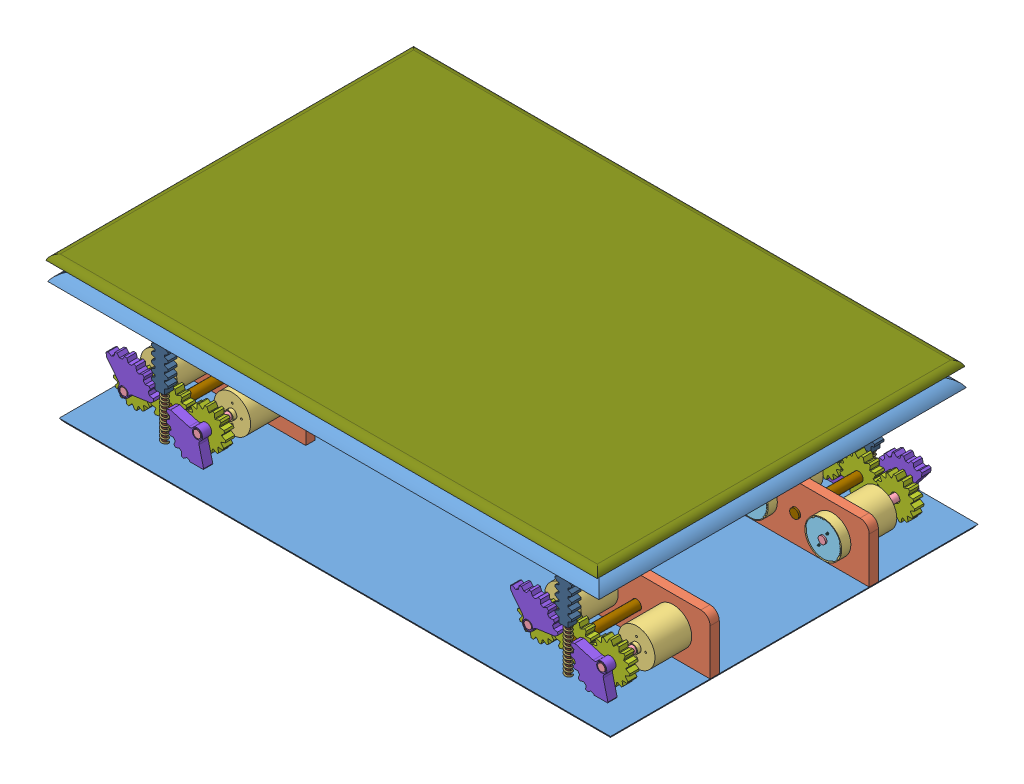
SolidWorks assembly Final Assembly, configuration Default. Lengths in mm.
Overall size (303.51 82.44 203.65).
112 component instances, 16 part files, 27 mates.
Components (placement in the parent):
- Assem6^Final Assembly-1: Assem6^Final Assembly [Default] at (14.902 -247.6382 47.2296) size (300 5 200) (virtual)
  - Floor-1: Floor [Default] at (40.4183 145.2122 322.6651) x (1 0 0) z (0 -1 0) size (300 200 5)
- Main assembly-1: Main assembly [Default] at (183.7252 -136.3252 264.8506) size (80 37.19 50)
  - motor holder-1: motor holder [Default] at (33.3269 70.8172 72.9987) size (80 30 5)
  - Motor-1: Motor [Default] at (25.9091 64.8426 109.725) x (0.51883 -0.854877 0) z (0 0 -1) size (20 20 50)
    - motorcover-1: motorcover [Default] at (7.4227 18.4991 11.7262) size (20 20 32)
    - dynamo-1: dynamo [Default] at (7.4227 18.4991 32.5262) x (0.962292 0.27202 0) z (0 0 -1) size (15 15 50)
    - Backcover-1: Backcover [Default] at (7.4227 18.4991 40.9262) size (19.2 19.2 0.8)
    - pin-1: pin [Default] at (28.5286 14.4912 41.7262) x (1 0 0) z (0 0 -1) size (1.25 1 1.6)
    - pin-2: pin [Default] at (37.5286 14.4917 41.7262) x (1 0 0) z (0 0 -1) size (1.25 1 1.6)
  - Motor-2: Motor [Default] at (46.523 67.3984 109.725) x (1 0 0) z (0 0 -1) size (20 20 50)
    - motorcover-1: motorcover [Default] at (7.4227 18.4991 11.7262) size (20 20 32)
    - dynamo-1: dynamo [Default] at (7.4227 18.4991 32.5262) x (0.962292 0.27202 0) z (0 0 -1) size (15 15 50)
    - Backcover-1: Backcover [Default] at (7.4227 18.4991 40.9262) size (19.2 19.2 0.8)
    - pin-1: pin [Default] at (28.5286 14.4912 41.7262) x (1 0 0) z (0 0 -1) size (1.25 1 1.6)
    - pin-2: pin [Default] at (37.5286 14.4917 41.7262) x (1 0 0) z (0 0 -1) size (1.25 1 1.6)
  - Spur gear-1: Spur gear [Default] at (13.9457 48.8992 107.1987) x (-0.96785 0.251527 0) z (0 0 1) size (21.02 20.91 5)
  - Spur gear-2: Spur gear [Default] at (53.9457 48.8992 107.1987) x (-0.973351 -0.229319 0) z (0 0 1) size (21.02 20.91 5)
  - Rack gear-1: Rack gear [Default] at (13.9457 48.8992 112.1987) x (0.990037 0.14081 0) z (0 0 1) size (24.29 19.79 5)
  - Rack gear-2: Rack gear [Default] at (53.9457 48.8992 112.1987) x (-0.960989 0.276587 0) z (0 0 1) size (24.29 19.79 5)
  - Spur gear-3: Spur gear [Default] at (33.9457 48.8992 107.1987) x (-0.999731 0.023183 0) z (0 0 1) size (21.02 20.91 5)
  - Rod1-2: Rod1 [Default] at (33.9457 48.8992 72.1987) size (5 5 40)
- Main assembly-2: Main assembly [Default] at (-36.2748 -136.3252 264.8506) size (80 37.19 50)
  - motor holder-1: motor holder [Default] at (33.3269 70.8172 72.9987) size (80 30 5)
  - Motor-1: Motor [Default] at (25.9091 64.8426 109.725) x (0.51883 -0.854877 0) z (0 0 -1) size (20 20 50)
    - motorcover-1: motorcover [Default] at (7.4227 18.4991 11.7262) size (20 20 32)
    - dynamo-1: dynamo [Default] at (7.4227 18.4991 32.5262) x (0.962292 0.27202 0) z (0 0 -1) size (15 15 50)
    - Backcover-1: Backcover [Default] at (7.4227 18.4991 40.9262) size (19.2 19.2 0.8)
    - pin-1: pin [Default] at (28.5286 14.4912 41.7262) x (1 0 0) z (0 0 -1) size (1.25 1 1.6)
    - pin-2: pin [Default] at (37.5286 14.4917 41.7262) x (1 0 0) z (0 0 -1) size (1.25 1 1.6)
  - Motor-2: Motor [Default] at (46.523 67.3984 109.725) x (1 0 0) z (0 0 -1) size (20 20 50)
    - motorcover-1: motorcover [Default] at (7.4227 18.4991 11.7262) size (20 20 32)
    - dynamo-1: dynamo [Default] at (7.4227 18.4991 32.5262) x (0.962292 0.27202 0) z (0 0 -1) size (15 15 50)
    - Backcover-1: Backcover [Default] at (7.4227 18.4991 40.9262) size (19.2 19.2 0.8)
    - pin-1: pin [Default] at (28.5286 14.4912 41.7262) x (1 0 0) z (0 0 -1) size (1.25 1 1.6)
    - pin-2: pin [Default] at (37.5286 14.4917 41.7262) x (1 0 0) z (0 0 -1) size (1.25 1 1.6)
  - Spur gear-1: Spur gear [Default] at (13.9457 48.8992 107.1987) x (-0.96785 0.251527 0) z (0 0 1) size (21.02 20.91 5)
  - Spur gear-2: Spur gear [Default] at (53.9457 48.8992 107.1987) x (-0.973351 -0.229319 0) z (0 0 1) size (21.02 20.91 5)
  - Rack gear-1: Rack gear [Default] at (13.9457 48.8992 112.1987) x (0.990037 0.14081 0) z (0 0 1) size (24.29 19.79 5)
  - Rack gear-2: Rack gear [Default] at (53.9457 48.8992 112.1987) x (-0.960989 0.276587 0) z (0 0 1) size (24.29 19.79 5)
  - Spur gear-3: Spur gear [Default] at (33.9457 48.8992 107.1987) x (-0.999731 0.023183 0) z (0 0 1) size (21.02 20.91 5)
  - Rod1-2: Rod1 [Default] at (33.9457 48.8992 72.1987) size (5 5 40)
- Pinion assembly with spring-1: Pinion assembly with spring [Default] at (-23.5736 0.0132 350.0039) x (1 0 0) z (0 -1 0) size (9 6.09 65.24)
  - pinion gear-1: pinion gear [Default] at (18.4826 32.0454 18.0009) x (0 0 1) z (0 -1 0) size (40 9 5)
  - Rod-1: Rod [Default] at (20.9826 29.4437 42.4391) x (-0.885268 -0.465081 0) z (0 0 1) size (2 2 60)
  - spring-1: spring [Default] at (20.9826 29.4437 61.9854) x (-0.695169 0.718847 0) z (0.718847 0.695169 0) size (4 30.64 4.62)
  - base-1: base [Default] at (20.9826 29.4437 102.4391) x (-0.953699 0.300764 0) z (0 0 1) size (4 4 0.4)
- Pinion assembly with spring-2: Pinion assembly with spring [Default] at (196.0946 0.0132 350.0039) x (1 0 0) z (0 -1 0) size (9 6.09 65.24)
  - pinion gear-1: pinion gear [Default] at (18.4826 32.0454 18.0009) x (0 0 1) z (0 -1 0) size (40 9 5)
  - Rod-1: Rod [Default] at (20.9826 29.4437 42.4391) x (-0.885268 -0.465081 0) z (0 0 1) size (2 2 60)
  - spring-1: spring [Default] at (20.9826 29.4437 61.9854) x (-0.695169 0.718847 0) z (0.718847 0.695169 0) size (4 30.64 4.62)
  - base-1: base [Default] at (20.9826 29.4437 102.4391) x (-0.953699 0.300764 0) z (0 0 1) size (4 4 0.4)
- Pinion assembly with spring-3: Pinion assembly with spring [Default] at (-24.0061 0.0132 185.0039) x (1 0 0) z (0 -1 0) size (9 6.09 65.24)
  - pinion gear-1: pinion gear [Default] at (18.4826 32.0454 18.0009) x (0 0 1) z (0 -1 0) size (40 9 5)
  - Rod-1: Rod [Default] at (20.9826 29.4437 42.4391) x (-0.885268 -0.465081 0) z (0 0 1) size (2 2 60)
  - spring-1: spring [Default] at (20.9826 29.4437 61.9854) x (-0.695169 0.718847 0) z (0.718847 0.695169 0) size (4 30.64 4.62)
  - base-1: base [Default] at (20.9826 29.4437 102.4391) x (-0.953699 0.300764 0) z (0 0 1) size (4 4 0.4)
- Pinion assembly with spring-4: Pinion assembly with spring [Default] at (195.948 0.0132 185.0039) x (1 0 0) z (0 -1 0) size (9 6.09 65.24)
  - pinion gear-1: pinion gear [Default] at (18.4826 32.0454 18.0009) x (0 0 1) z (0 -1 0) size (40 9 5)
  - Rod-1: Rod [Default] at (20.9826 29.4437 42.4391) x (-0.885268 -0.465081 0) z (0 0 1) size (2 2 60)
  - spring-1: spring [Default] at (20.9826 29.4437 61.9854) x (-0.695169 0.718847 0) z (0.718847 0.695169 0) size (4 30.64 4.62)
  - base-1: base [Default] at (20.9826 29.4437 102.4391) x (-0.953699 0.300764 0) z (0 0 1) size (4 4 0.4)
- Floor-2: Floor [Default] at (52.166 -37.9877 227.3464) x (1 0 0) z (0 1 0) size (300 200 5)
- piezo-holder-1: piezo-holder [Default] at (-34.8513 -27.9877 210.389) x (1 0 0) z (0 -1 0) size (5 5 5)
- piezo-holder-2: piezo-holder [Default] at (244.0539 -27.9877 207.1198) x (1 0 0) z (0 -1 0) size (5 5 5)
- piezo-holder-3: piezo-holder [Default] at (-35.2045 -27.9877 389.6264) x (1 0 0) z (0 -1 0) size (5 5 5)
- piezo-holder-4: piezo-holder [Default] at (243.3873 -27.9877 391.1396) x (1 0 0) z (0 -1 0) size (5 5 5)
- Spring2-2: Spring2 [Default] at (244.0033 -32.8878 207.2172) x (1 0 0) z (0 -0.048057 0.998845) size (6.2 5.2 7.16)
- Spring2-3: Spring2 [Default] at (243.1158 -33.0876 391.053) x (1 0 0) z (0 -0.048057 0.998845) size (6.2 5.2 7.16)
- Spring2-5: Spring2 [Default] at (-35.5943 -32.8878 389.5788) x (1 0 0) z (0 -0.048057 0.998845) size (6.2 5.2 7.16)
- Spring2-6: Spring2 [Default] at (-34.8112 -32.8878 210.5266) x (1 0 0) z (0 -0.048057 0.998845) size (6.2 5.2 7.16)
- footbase-2: footbase [Default] at (2.9353 -27.9877 217.7245) x (1 0 0) z (0 1 0) size (300 200 10)
- Main assembly-5: Main assembly [Default] at (31.6166 -136.3252 329.248) x (-1 0 0) z (0 0 -1) size (80 37.19 50)
  - motor holder-1: motor holder [Default] at (33.3269 70.8172 72.9987) size (80 30 5)
  - Motor-1: Motor [Default] at (25.9091 64.8426 109.725) x (0.51883 -0.854877 0) z (0 0 -1) size (20 20 50)
    - motorcover-1: motorcover [Default] at (7.4227 18.4991 11.7262) size (20 20 32)
    - dynamo-1: dynamo [Default] at (7.4227 18.4991 32.5262) x (0.962292 0.27202 0) z (0 0 -1) size (15 15 50)
    - Backcover-1: Backcover [Default] at (7.4227 18.4991 40.9262) size (19.2 19.2 0.8)
    - pin-1: pin [Default] at (28.5286 14.4912 41.7262) x (1 0 0) z (0 0 -1) size (1.25 1 1.6)
    - pin-2: pin [Default] at (37.5286 14.4917 41.7262) x (1 0 0) z (0 0 -1) size (1.25 1 1.6)
  - Motor-2: Motor [Default] at (46.523 67.3984 109.725) x (1 0 0) z (0 0 -1) size (20 20 50)
    - motorcover-1: motorcover [Default] at (7.4227 18.4991 11.7262) size (20 20 32)
    - dynamo-1: dynamo [Default] at (7.4227 18.4991 32.5262) x (0.962292 0.27202 0) z (0 0 -1) size (15 15 50)
    - Backcover-1: Backcover [Default] at (7.4227 18.4991 40.9262) size (19.2 19.2 0.8)
    - pin-1: pin [Default] at (28.5286 14.4912 41.7262) x (1 0 0) z (0 0 -1) size (1.25 1 1.6)
    - pin-2: pin [Default] at (37.5286 14.4917 41.7262) x (1 0 0) z (0 0 -1) size (1.25 1 1.6)
  - Spur gear-1: Spur gear [Default] at (13.9457 48.8992 107.1987) x (-0.96785 0.251527 0) z (0 0 1) size (21.02 20.91 5)
  - Spur gear-2: Spur gear [Default] at (53.9457 48.8992 107.1987) x (-0.973351 -0.229319 0) z (0 0 1) size (21.02 20.91 5)
  - Rack gear-1: Rack gear [Default] at (13.9457 48.8992 112.1987) x (0.990037 0.14081 0) z (0 0 1) size (24.29 19.79 5)
  - Rack gear-2: Rack gear [Default] at (53.9457 48.8992 112.1987) x (-0.960989 0.276587 0) z (0 0 1) size (24.29 19.79 5)
  - Spur gear-3: Spur gear [Default] at (33.9457 48.8992 107.1987) x (-0.999731 0.023183 0) z (0 0 1) size (21.02 20.91 5)
  - Rod1-2: Rod1 [Default] at (33.9457 48.8992 72.1987) size (5 5 40)
- Main assembly-6: Main assembly [Default] at (251.6166 -136.3252 329.248) x (-1 0 0) z (0 0 -1) size (80 37.19 50)
  - motor holder-1: motor holder [Default] at (33.3269 70.8172 72.9987) size (80 30 5)
  - Motor-1: Motor [Default] at (25.9091 64.8426 109.725) x (0.51883 -0.854877 0) z (0 0 -1) size (20 20 50)
    - motorcover-1: motorcover [Default] at (7.4227 18.4991 11.7262) size (20 20 32)
    - dynamo-1: dynamo [Default] at (7.4227 18.4991 32.5262) x (0.962292 0.27202 0) z (0 0 -1) size (15 15 50)
    - Backcover-1: Backcover [Default] at (7.4227 18.4991 40.9262) size (19.2 19.2 0.8)
    - pin-1: pin [Default] at (28.5286 14.4912 41.7262) x (1 0 0) z (0 0 -1) size (1.25 1 1.6)
    - pin-2: pin [Default] at (37.5286 14.4917 41.7262) x (1 0 0) z (0 0 -1) size (1.25 1 1.6)
  - Motor-2: Motor [Default] at (46.523 67.3984 109.725) x (1 0 0) z (0 0 -1) size (20 20 50)
    - motorcover-1: motorcover [Default] at (7.4227 18.4991 11.7262) size (20 20 32)
    - dynamo-1: dynamo [Default] at (7.4227 18.4991 32.5262) x (0.962292 0.27202 0) z (0 0 -1) size (15 15 50)
    - Backcover-1: Backcover [Default] at (7.4227 18.4991 40.9262) size (19.2 19.2 0.8)
    - pin-1: pin [Default] at (28.5286 14.4912 41.7262) x (1 0 0) z (0 0 -1) size (1.25 1 1.6)
    - pin-2: pin [Default] at (37.5286 14.4917 41.7262) x (1 0 0) z (0 0 -1) size (1.25 1 1.6)
  - Spur gear-1: Spur gear [Default] at (13.9457 48.8992 107.1987) x (-0.96785 0.251527 0) z (0 0 1) size (21.02 20.91 5)
  - Spur gear-2: Spur gear [Default] at (53.9457 48.8992 107.1987) x (-0.973351 -0.229319 0) z (0 0 1) size (21.02 20.91 5)
  - Rack gear-1: Rack gear [Default] at (13.9457 48.8992 112.1987) x (0.990037 0.14081 0) z (0 0 1) size (24.29 19.79 5)
  - Rack gear-2: Rack gear [Default] at (53.9457 48.8992 112.1987) x (-0.960989 0.276587 0) z (0 0 1) size (24.29 19.79 5)
  - Spur gear-3: Spur gear [Default] at (33.9457 48.8992 107.1987) x (-0.999731 0.023183 0) z (0 0 1) size (21.02 20.91 5)
  - Rod1-2: Rod1 [Default] at (33.9457 48.8992 72.1987) size (5 5 40)
Mates (geometry in assembly coordinates):
- Coincident3: coincident: line of Assem6^Final Assembly-1/Floor-1 through (257.6709 -102.4259 197.0493) axis (0 0 1); moEndPointRef_w of Main assembly-1/motor holder-1
- Distance2: distance = 15 mm: plane of Main assembly-1/Rack gear-2 through (237.6709 -87.4259 382.0493) normal (0 0 1); line of Assem6^Final Assembly-1/Floor-1 through (257.6709 -102.4259 397.0493) axis (-1 0 0)
- Coincident4: coincident anti-aligned: plane of Assem6^Final Assembly-1/Floor-1 through (55.3202 -102.4259 369.8948) normal (0 1 0); plane of Main assembly-1/motor holder-1 through (177.6709 -102.4259 342.8493) normal (0 -1 0)
- Coincident5: coincident aligned: line of Assem6^Final Assembly-1/Floor-1 through (-42.3291 -102.4259 397.0493) axis (0 0 -1); line of Main assembly-2/motor holder-1 through (-42.3291 -102.4259 342.8493) axis (0 0 -1)
- Distance3: distance = 15 mm: plane of Main assembly-2/Rack gear-1 through (-22.3291 -87.4259 382.0493) normal (0 0 1); line of Assem6^Final Assembly-1/Floor-1 through (257.6709 -102.4259 397.0493) axis (-1 0 0)
- Coincident12: coincident aligned: plane of Main assembly-2/Rack gear-2 through (17.6709 -87.4259 382.0493) normal (0 0 1); plane of Pinion assembly with spring-1/pinion gear-1 through (-5.091 -17.9877 382.0493) normal (0 0 1)
- Coincident14: coincident aligned: plane of Assem6^Final Assembly-1/Floor-1 through (55.3202 -102.4259 369.8948) normal (0 1 0); plane of Pinion assembly with spring-1/base-1 through (-2.591 -102.4259 379.4476) normal (0 1 0)
- Coincident15: coincident aligned: plane of Main assembly-1/Rack gear-2 through (237.6709 -87.4259 382.0493) normal (0 0 1); plane of Pinion assembly with spring-2/pinion gear-1 through (214.5771 -17.9877 382.0493) normal (0 0 1)
- Coincident19: coincident anti-aligned: plane of Assem6^Final Assembly-1/Floor-1 through (55.3202 -102.4259 369.8948) normal (0 1 0); circle of Pinion assembly with spring-2/base-1
- Coincident21: coincident anti-aligned: plane of Assem6^Final Assembly-1/Floor-1 through (55.3202 -102.4259 369.8948) normal (0 1 0); circle of Pinion assembly with spring-3/base-1
- Coincident23: coincident anti-aligned: plane of Assem6^Final Assembly-1/Floor-1 through (55.3202 -102.4259 369.8948) normal (0 1 0); circle of Pinion assembly with spring-4/base-1
- Coincident26: coincident: plane of assembly; plane of Pinion assembly with spring-4/pinion gear-1 through (214.4305 -17.9877 212.0493) normal (0 1 0); plane of Floor-2 through (52.166 -37.9877 227.3464) normal (0 -1 0)
- Parallel5: parallel anti-aligned: line of Assem6^Final Assembly-1/Floor-1 through (257.6709 -102.4259 197.0493) axis (0 0 1); line of Floor-2 through (254.5166 -37.9877 400.1919) axis (0 0 -1)
- Coincident27: coincident: point of Floor-2; circle of piezo-holder-1
- Coincident28: coincident: point of Floor-2; circle of piezo-holder-2
- Coincident29: coincident: point of Floor-2; circle of piezo-holder-3
- Coincident30: coincident: point of Floor-2; circle of piezo-holder-4
- Tangent4: tangent: plane of Floor-2 through (52.166 -32.9877 227.3464) normal (0 1 0); face of Spring2-2
- Tangent5: tangent: plane of Floor-2 through (52.166 -32.9877 227.3464) normal (0 1 0); face of Spring2-3
- Tangent9: tangent: plane of Floor-2 through (52.166 -32.9877 227.3464) normal (0 1 0); face of Spring2-5
- Tangent10: tangent: plane of Floor-2 through (52.166 -32.9877 227.3464) normal (0 1 0); face of Spring2-6
- Coincident31: coincident anti-aligned: plane of Pinion assembly with spring-4/pinion gear-1 through (214.4305 -37.9877 212.0493) normal (0 1 0); plane of Floor-2 through (52.166 -37.9877 227.3464) normal (0 -1 0)
- Coincident37: coincident anti-aligned: plane of piezo-holder-1 through (-34.8513 -27.9877 210.389) normal (0 1 0); plane of footbase-2 through (2.9353 -27.9877 217.7245) normal (0 -1 0)
- Coincident46: coincident: line of Assem6^Final Assembly-1/Floor-1 through (-42.3291 -102.4259 397.0493) axis (0 0 -1); unknown of Main assembly-5/motor holder-1
- Distance6: distance = 15 mm: plane of Main assembly-5/Rack gear-2 through (-22.3291 -87.4259 212.0493) normal (0 0 -1); line of Assem6^Final Assembly-1/Floor-1 through (-42.3291 -102.4259 197.0493) axis (1 0 0)
- Coincident50: coincident: line of Assem6^Final Assembly-1/Floor-1 through (257.6709 -102.4259 197.0493) axis (0 0 1); unknown of Main assembly-6/motor holder-1
- Distance8: distance = 15 mm: plane of Main assembly-6/Rack gear-2 through (197.6709 -87.4259 212.0493) normal (0 0 -1); line of Assem6^Final Assembly-1/Floor-1 through (-42.3291 -102.4259 197.0493) axis (1 0 0)
